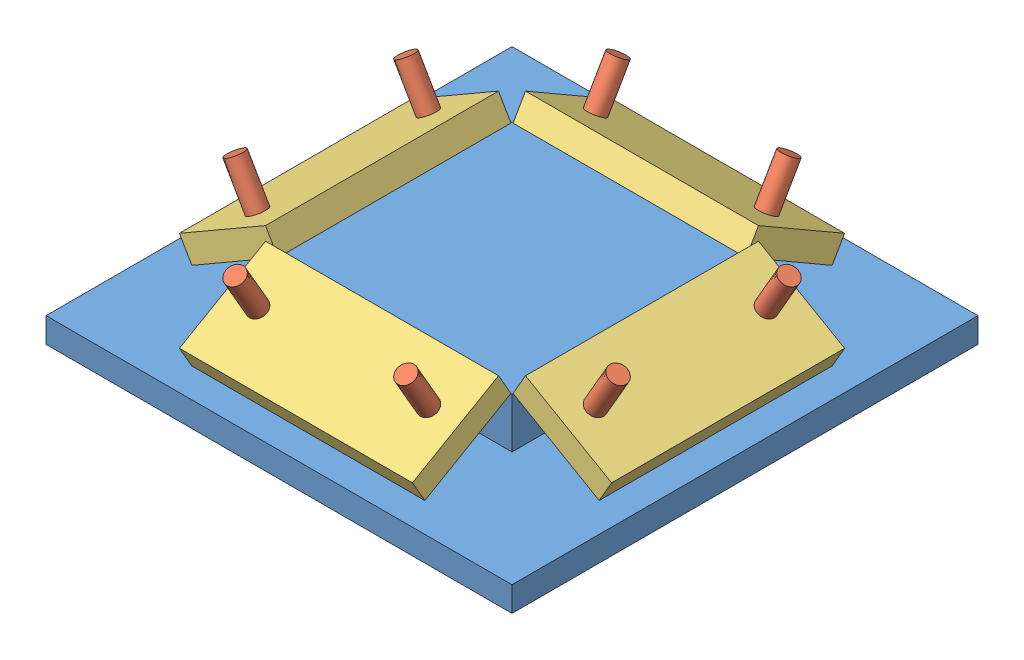
SolidWorks assembly Assem4, configuration Default. Lengths in mm.
Overall size (30 7.55 30).
13 component instances, 3 part files, 13 mates.
Components (placement in the parent):
- 3D Print Base-1: 3D Print Base [Default] at (-26.0966 5.527 15.47) size (30 4.8 30)
- bentpin prototype-1: bentpin prototype [Default] at (-16.5966 8.077 10.47) size (1.2 7.55 3.45)
- bentpin prototype-2: bentpin prototype [Default] at (-5.5966 8.077 10.47) size (1.2 7.55 3.45)
- 3D Print Photodiode-1: 3D Print Photodiode [Default] at (-11.0966 8.877 10.5504) x (1 0 0) z (0 -0.5 0.866025) size (15 1.6 6.4)
- 3D Print Photodiode-2: 3D Print Photodiode [Default] at (-11.0966 8.877 -9.6104) x (-1 0 0) z (0 -0.5 -0.866025) size (15 1.6 6.4)
- bentpin prototype-3: bentpin prototype [Default] at (-5.5966 8.077 -9.53) x (-1 0 0) z (0 0 -1) size (1.2 7.55 3.45)
- bentpin prototype-4: bentpin prototype [Default] at (-16.5966 8.077 -9.53) x (-1 0 0) z (0 0 -1) size (1.2 7.55 3.45)
- 3D Print Photodiode-3: 3D Print Photodiode [Default] at (-21.177 8.877 0.47) x (0 0 1) z (-0.866025 -0.5 0) size (15 1.6 6.4)
- bentpin prototype-5: bentpin prototype [Default] at (-21.0966 8.077 -5.03) x (0 0 1) z (-1 0 0) size (1.2 7.55 3.45)
- bentpin prototype-6: bentpin prototype [Default] at (-21.0966 8.077 5.97) x (0 0 1) z (-1 0 0) size (1.2 7.55 3.45)
- 3D Print Photodiode-4: 3D Print Photodiode [Default] at (-1.0162 8.877 0.47) x (0 0 -1) z (0.866025 -0.5 0) size (15 1.6 6.4)
- bentpin prototype-7: bentpin prototype [Default] at (-1.0966 8.077 -5.03) x (0 0 -1) z (1 0 0) size (1.2 7.55 3.45)
- bentpin prototype-8: bentpin prototype [Default] at (-1.0966 8.077 5.97) x (0 0 -1) z (1 0 0) size (1.2 7.55 3.45)
Mates (geometry in assembly coordinates):
- Concentric1: concentric aligned: cylinder of 3D Print Base-1 through (-5.5966 5.527 10.47) axis (0 1 0) radius 0.6; cylinder of bentpin prototype-2 through (-5.5966 8.077 10.47) axis (0 1 0) radius 0.6
- Coincident2: coincident aligned: plane of 3D Print Base-1 through (-26.0966 5.527 15.47) normal (0 -1 0); plane of bentpin prototype-2 through (-5.5966 5.527 10.47) normal (0 -1 0)
- Concentric2: concentric aligned: cylinder of 3D Print Base-1 through (-16.5966 5.527 10.47) axis (0 1 0) radius 0.6; cylinder of bentpin prototype-1 through (-16.5966 8.077 10.47) axis (0 1 0) radius 0.6
- Coincident3: coincident aligned: plane of 3D Print Base-1 through (-26.0966 5.527 15.47) normal (0 -1 0); plane of bentpin prototype-1 through (-16.5966 5.527 10.47) normal (0 -1 0)
- Concentric3: concentric aligned: cylinder of bentpin prototype-2 through (-5.5966 8.877 10.5504) axis (0 0.866025 0.5) radius 0.6; cylinder of 3D Print Photodiode-1 through (-5.5966 1.6024 6.3504) axis (0 0.866025 0.5) radius 0.6
- Coincident4: coincident anti-aligned: circle of bentpin prototype-2; plane of 3D Print Photodiode-1 through (-11.0966 8.877 10.5504) normal (0 -0.866025 -0.5)
- Concentric5: concentric aligned: cylinder of 3D Print Photodiode-3 through (-16.977 1.6024 -5.03) axis (-0.5 0.866025 0) radius 0.6; cylinder of bentpin prototype-5 through (-21.177 8.877 -5.03) axis (-0.5 0.866025 0) radius 0.6
- Coincident6: coincident anti-aligned: plane of 3D Print Photodiode-3 through (-21.177 8.877 0.47) normal (0.5 -0.866025 0); circle of bentpin prototype-5
- Concentric6: concentric aligned: cylinder of 3D Print Photodiode-3 through (-16.977 1.6024 5.97) axis (-0.5 0.866025 0) radius 0.6; cylinder of bentpin prototype-6 through (-21.177 8.877 5.97) axis (-0.5 0.866025 0) radius 0.6
- Coincident7: coincident anti-aligned: plane of 3D Print Photodiode-3 through (-21.177 8.877 0.47) normal (0.5 -0.866025 0); circle of bentpin prototype-6
- Concentric7: concentric aligned: cylinder of 3D Print Base-1 through (-21.0966 5.527 -5.03) axis (0 1 0) radius 0.6; cylinder of bentpin prototype-5 through (-21.0966 8.077 -5.03) axis (0 1 0) radius 0.6
- Concentric8: concentric aligned: cylinder of 3D Print Base-1 through (-21.0966 5.527 5.97) axis (0 1 0) radius 0.6; cylinder of bentpin prototype-6 through (-21.0966 8.077 5.97) axis (0 1 0) radius 0.6
- Coincident8: coincident aligned: plane of 3D Print Base-1 through (-26.0966 5.527 15.47) normal (0 -1 0); plane of bentpin prototype-5 through (-21.0966 5.527 -5.03) normal (0 -1 0)
